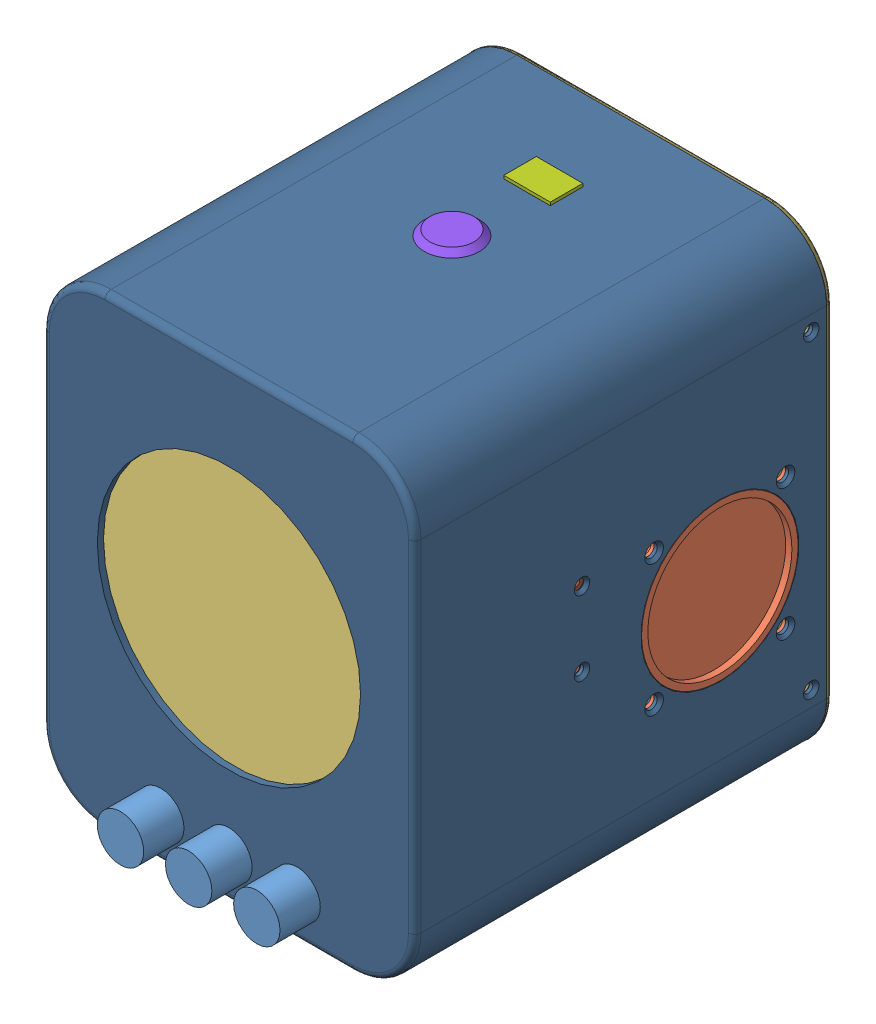
SolidWorks assembly 音响装配, configuration 默认. Lengths in mm.
Overall size (120 151.8 150).
14 component instances, 13 part files, 37 mates.
Components (placement in the parent):
- 功放-1: 功放 [默认] at origin size (70 22 72.5)
- 喇叭-1: 喇叭 [默认] at (-58 65.5 -67.75) x (0 0 1) z (0 -1 0) size (53 32 53)
- 喇叭-2: 喇叭 [默认] at (58 65.5 -67.75) x (0 -1 0) z (0 0 1) size (53 32 53)
- 瓶子-1: 瓶子 [默认] at (0 77 -6.25) size (100 110 35)
- 电磁铁-1: 电磁铁 [默认] at (0 77 -6.25) x (0.576096 -0.817382 0) z (0.817382 0.576096 0) size (40 20 40)
- mos-1: mos [默认] at (0 0 -71.5) size (47 15 25.5)
- 充电口-1: 充电口 [默认] at (0 30 -106.25) x (0 1 0) z (1 0 0) size (10 18 10)
- 船开-1: 船开 [默认] at (0 132 -70.75) size (15 17 10.5)
- 自锁开关16mm-1: 自锁开关16mm [默认] at (0 148 -41.25) x (0 0 -1) z (0 1 0) size (17.8 17.8 35.3)
- 音响led-1: 音响led [默认] at (0 77 8.75) size (106 103.83 5)
- 外壳A-1: 外壳A [默认] at (0 77 28.75) size (120 150 133)
- 零件4^音响装配-1: 零件4^音响装配 [默认] at origin (virtual)
- 电磁铁固定-1: 电磁铁固定 [默认] at (0 77 -29.25) x (-1 0 0) z (0 1 0) size (116 23 86)
- 外壳B-1: 外壳B [默认] at (0 77 -102.25) x (-1 0 0) z (0 0 -1) size (120 150 12)
Mates (geometry in assembly coordinates):
- 同心1: concentric anti-aligned: cylinder of 喇叭-1 through (-38 65.5 -67.75) axis (1 0 0) radius 22.75; cylinder of 喇叭-2 through (38 65.5 -67.75) axis (-1 0 0) radius 22.75
- 重合3: coincident aligned: plane of 功放-1 through (-35 22 28.75) normal (0 0 1); plane of 瓶子-1 through (0 77 28.75) normal (0 0 1)
- 距离2: distance = 10 mm anti-aligned: plane of 瓶子-1 through (0 32 -6.25) normal (0 -1 0); plane of 功放-1 through (0 22 0) normal (0 1 0)
- 同心2: concentric anti-aligned: cylinder of 瓶子-1 through (0 77 28.75) axis (0 0 -1) radius 50; cylinder of 电磁铁-1 through (0 77 -26.25) axis (0 0 1) radius 20
- 重合5: coincident anti-aligned: plane of 瓶子-1 through (0 77 -6.25) normal (0 0 -1); plane of 电磁铁-1 through (0 77 -6.25) normal (0 0 1)
- 平行2: parallel anti-aligned: line of 功放-1 through (-35 22 28.75) axis (1 0 0); line of 瓶子-1 through (21.7945 32 28.75) axis (-1 0 0)
- 重合7: coincident aligned: plane of 功放-1 through (0 0 0) normal (1 0 0); plane of 瓶子-1 through (0 77 -6.25) normal (1 0 0)
- 宽度1: width anti-aligned: plane of 功放-1 through (35 22 -28.75) normal (1 0 0); plane of 功放-1 through (-35 22 -28.75) normal (-1 0 0); plane of 喇叭-2 through (28 65.5 -67.75) normal (-1 0 0); plane of 喇叭-1 through (-28 65.5 -67.75) normal (1 0 0)
- 重合8: coincident aligned: plane of 功放-1 through (0 0 0) normal (0 -1 0); plane of mos-1 through (0 0 -71.5) normal (0 -1 0)
- 距离3: distance = 30 mm anti-aligned: plane of mos-1 through (-23.5 15 -58.75) normal (0 0 1); plane of 功放-1 through (-35 22 -28.75) normal (0 0 -1)
- 宽度2: width anti-aligned: plane of 功放-1 through (35 22 -28.75) normal (1 0 0); plane of 功放-1 through (-35 22 -28.75) normal (-1 0 0); plane of mos-1 through (-23.5 15 -58.75) normal (-1 0 0); plane of mos-1 through (23.5 15 -58.75) normal (1 0 0)
- 距离4: distance = 100 mm aligned: plane of 充电口-1 through (0 30 -106.25) normal (0 0 -1); plane of 瓶子-1 through (0 77 -6.25) normal (0 0 -1)
- 重合11: coincident aligned: plane of 充电口-1 through (0 30 -106.25) normal (1 0 0)
- 距离5: distance = 30 mm aligned: plane of 充电口-1 through (0 30 -106.25) normal (0 1 0)
- 重合12: coincident anti-aligned: plane of 自锁开关16mm-1 through (0 148 -41.25) normal (-1 0 0)
- 重合13: coincident anti-aligned: plane of 自锁开关16mm-1 through (0 148 -41.25) normal (0 -1 0); plane of 外壳A-1 through (-40 148 30.75) normal (0 1 0)
- 距离6: distance = 35 mm aligned: plane of 自锁开关16mm-1 through (0 148 -41.25) normal (0 0 -1); plane of 瓶子-1 through (0 77 -6.25) normal (0 0 -1)
- 距离7: distance = 60 mm anti-aligned: plane of 船开-1 through (-7 148 -66.25) normal (0 0 1); plane of 瓶子-1 through (0 77 -6.25) normal (0 0 -1)
- 宽度3: width anti-aligned: plane of 喇叭-1 through (-28 65.5 -67.75) normal (1 0 0); plane of 船开-1 through (28 65.5 -67.75) normal (-1 0 0); plane of 喇叭-2 through (-7 148 -75.25) normal (-1 0 0); plane of 船开-1 through (7 148 -75.25) normal (1 0 0)
- 重合16: coincident aligned: plane of 船开-1 through (0 148 -70.75) normal (0 -1 0); plane of 自锁开关16mm-1 through (0 148 -41.25) normal (0 -1 0)
- 同心3: concentric aligned: cylinder of 瓶子-1 through (0 77 28.75) axis (0 0 -1) radius 50; cylinder of 音响led-1 through (0 77 13.75) axis (0 0 -1) radius 50
- 宽度4: width anti-aligned: plane of 瓶子-1 through (0 77 28.75) normal (0 0 1); plane of 音响led-1 through (0 77 -6.25) normal (0 0 -1); plane of 瓶子-1 through (0 77 8.75) normal (0 0 -1); plane of 音响led-1 through (0 77 13.75) normal (0 0 1)
- 平行3: parallel aligned: plane of 功放-1 through (-35 22 -28.75) normal (-1 0 0); plane of 音响led-1 through (15 142 3.75) normal (-1 0 0)
- 在位1: in place: plane of 瓶子-1 through (0 77 28.75) normal (0 0 1); plane of ? through (0 0 28.75) normal (0 0 1); moOrthogonalPlaneRef_w of 瓶子-1 through (0 77 28.75) normal (0 0 1); plane of ? through (0 0 28.75) normal (0 1 0); plane of 瓶子-1 through (0 77 28.75) normal (0 0 1); plane of ? through (0 0 28.75) normal (1 0 0); plane of 瓶子-1 through (0 77 28.75) normal (0 0 1); unknown of 外壳A-1
- 重合17: coincident aligned: plane of 瓶子-1; plane of 外壳A-1
- 重合18: coincident aligned: moOrthogonalPlaneRef_w of 瓶子-1 through (0 77 28.75) normal (0 1 0); plane of 外壳A-1 through (0 77 28.75) normal (0 1 0)
- 重合19: coincident anti-aligned: moOrthogonalPlaneRef_w of 瓶子-1 through (0 77 28.75) normal (-1 0 0); plane of 外壳A-1 through (0 77 28.75) normal (1 0 0)
- 重合20: coincident anti-aligned: plane of 喇叭-2 through (58 65.5 -67.75) normal (1 0 0); plane of 外壳A-1 through (58 128 -294.3437) normal (-1 0 0)
- 距离8: distance = 35 mm anti-aligned: plane of 喇叭-2 through (57 92 -41.25) normal (0 0 1); plane of 瓶子-1 through (0 77 -6.25) normal (0 0 -1)
- 距离9: distance = 70 mm aligned: plane of 功放-1 through (0 22 0) normal (0 1 0); plane of 喇叭-2 through (57 92 -41.25) normal (0 1 0)
- 重合23: coincident anti-aligned: plane of 外壳A-1 through (-58 18 -294.3437) normal (1 0 0); plane of 电磁铁固定-1 through (-58 57 -26.25) normal (-1 0 0)
- 重合24: coincident anti-aligned: plane of 电磁铁-1 through (0 77 -26.25) normal (0 0 -1); plane of 电磁铁固定-1 through (0 77 -26.25) normal (0 0 1)
- 同心4: concentric anti-aligned: cylinder of 电磁铁-1 through (0 77 -16.25) axis (0 0 -1) radius 2.5; cylinder of 电磁铁固定-1 through (0 77 -29.25) axis (0 0 1) radius 2.5
- 在位2: in place: plane of 外壳A-1 through (0 30 -102.25) normal (0 0 -1); plane of ? through (0 0 -102.25) normal (0 0 -1); plane of 外壳A-1 through (0 30 -102.25) normal (0 0 -1); plane of ? through (0 0 -102.25) normal (0 1 0); plane of 外壳A-1 through (0 30 -102.25) normal (0 0 -1); plane of ? through (0 0 -102.25) normal (-1 0 0); plane of 外壳A-1 through (0 30 -102.25) normal (0 0 -1); unknown of 外壳B-1
- 重合25: coincident aligned: plane of 外壳A-1; plane of 外壳B-1
- 重合26: coincident aligned: moOrthogonalPlaneRef_w of 外壳A-1 through (0 77 -102.25) normal (0 1 0); plane of 零件6^音响装配-1 through (0 77 -102.25) normal (0 1 0)
- 重合27: coincident anti-aligned: moOrthogonalPlaneRef_w of 外壳A-1 through (0 77 -102.25) normal (1 0 0); plane of 零件6^音响装配-1 through (0 77 -102.25) normal (-1 0 0)
